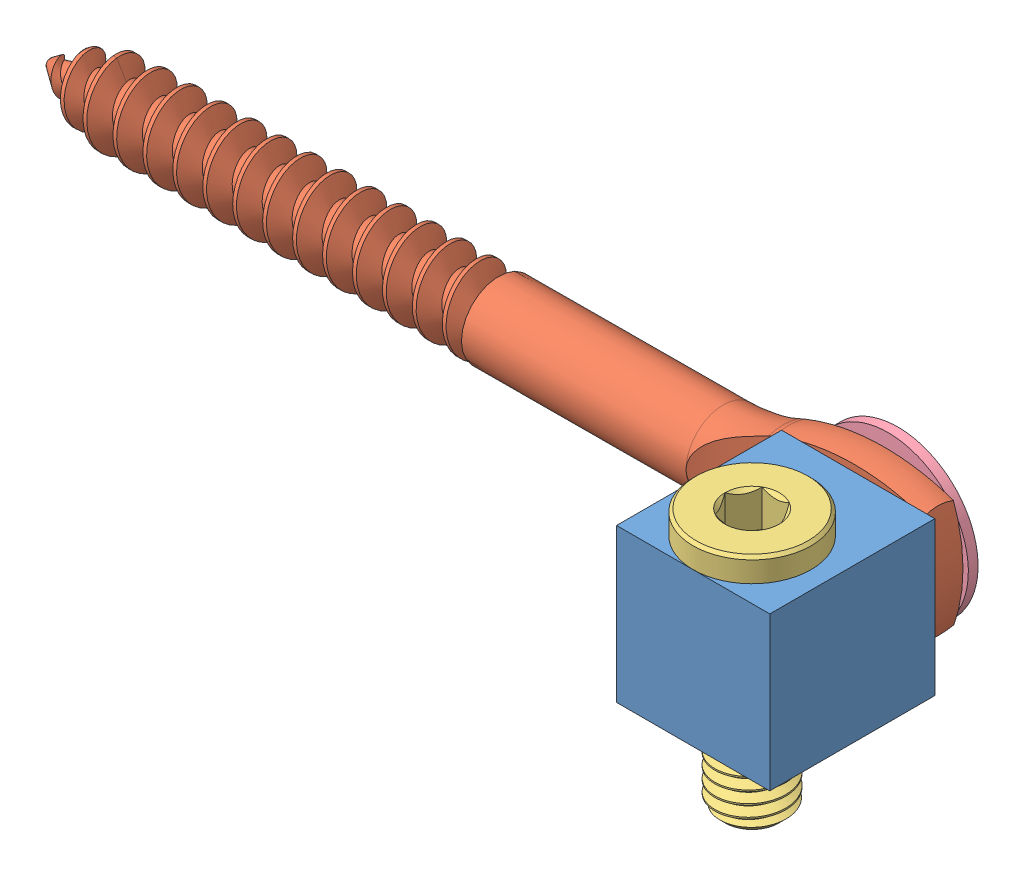
SolidWorks assembly Sample Rock Positioning Assembly 2, configuration Default. Lengths in mm.
Overall size (79.23 24.28 20.07).
4 component instances, 4 part files, 16 mates.
Components (placement in the parent):
- Sample Rock Positioning Bracket 2-1: Sample Rock Positioning Bracket 2 [Default] at (4.3735 9.6175 7.5401) size (13 13 14)
- 90171A554_SCREW HANGER-1: 90171A554_SCREW HANGER [90171A554] at (-65.4758 10.8048 6.2701) x (0 0 1) z (-0.99999 -0.004477 0) size (7.33 13.07 76.67)
- 90358A019_METRIC STL ULTRA-LOW-PROFILE SCKT HEAD SCREW-1: 90358A019_METRIC STL ULTRA-LOW-PROFILE SCKT HEAD SCREW [90358A019] at (4.3735 6.1175 16.5401) x (0 -1 0) z (0 0 1) size (22.63 10 10)
- 92137A523_CLASS 10.9 ALLOY STEEL BUTTON-HEAD CAP SCREW-1: 92137A523_CLASS 10.9 ALLOY STEEL BUTTON-HEAD CAP SCREW [92137A523] at (4.3735 11.1175 1.7001) x (-0.923728 -0.383049 0) z (0 0 -1) size (13.6 13.6 11.86)
Mates (geometry in assembly coordinates):
- Coincident3: coincident anti-aligned: plane of Sample Rock Positioning Bracket 2-1 through (4.3735 5.1175 16.5401) normal (0 1 0); plane of 91223A421_316 SS ULTRA-LOW-PROFILE SOCKET HEAD SCREW-1 through (4.3735 5.1175 22.5401) normal (0 -1 0)
- Concentric3: concentric anti-aligned: circle of Sample Rock Positioning Bracket 2-1; circle of 91223A421_316 SS ULTRA-LOW-PROFILE SOCKET HEAD SCREW-1
- Coincident4: coincident anti-aligned: plane of Sample Rock Positioning Bracket 2-1 through (4.3735 9.6175 7.5401) normal (0 0 -1); plane of 91290A173_BLACK-OXIDE CLASS 12.9 SOCKET HEAD CAP SCREW-1 through (4.3735 12.1175 7.5401) normal (0 0 1)
- Concentric4: concentric anti-aligned: circle of Sample Rock Positioning Bracket 2-1; circle of 91290A173_BLACK-OXIDE CLASS 12.9 SOCKET HEAD CAP SCREW-1
- Coincident6: coincident anti-aligned: plane of Sample Rock Positioning Bracket 2-1 through (-2.1265 16.1175 21.5401) normal (0 1 0); plane of 91223A442_316 SS ULTRA-LOW-PROFILE SOCKET HEAD SCREW-1 through (4.3735 16.1175 22.5401) normal (0 -1 0)
- Concentric5: concentric aligned: circle of Sample Rock Positioning Bracket 2-1; circle of 91223A442_316 SS ULTRA-LOW-PROFILE SOCKET HEAD SCREW-1
- Coincident7: coincident anti-aligned: plane of Sample Rock Positioning Bracket 2-1 through (4.3735 9.6175 7.5401) normal (0 0 -1); plane of 90171A554_SCREW HANGER-1 through (10.7803 -1.554 7.5401) normal (0 0 1)
- Concentric6: concentric aligned: circle of 90171A554_SCREW HANGER-1; cylinder of Sample Rock Positioning Bracket 2-1 through (4.3735 11.1175 7.5401) axis (0 0 -1) radius 2.5
- Coincident8: coincident anti-aligned: plane of 91290A312_BLACK-OXIDE CLASS 12.9 SOCKET HEAD CAP SCREW-1 through (4.3735 11.1175 5.0001) normal (0 0 1); plane of 90171A554_SCREW HANGER-1 through (10.7803 -1.554 5.0001) normal (0 0 -1)
- Concentric7: concentric aligned: circle of Sample Rock Positioning Bracket 2-1; circle of 91290A312_BLACK-OXIDE CLASS 12.9 SOCKET HEAD CAP SCREW-1
- Coincident9: coincident anti-aligned: plane of 90171A554_SCREW HANGER-1 through (10.7803 -1.554 5.0001) normal (0 0 -1); plane of 90358A016_METRIC STL ULTRA-LOW-PROFILE SCKT HEAD SCREW-1 through (4.3735 16.1175 5.0001) normal (0 0 1)
- Concentric8: concentric anti-aligned: circle of 90171A554_SCREW HANGER-1; circle of 90358A016_METRIC STL ULTRA-LOW-PROFILE SCKT HEAD SCREW-1
- Concentric9: concentric anti-aligned: circle of 90358A019_METRIC STL ULTRA-LOW-PROFILE SCKT HEAD SCREW-1; circle of Sample Rock Positioning Bracket 2-1
- Coincident12: coincident anti-aligned: plane of 90358A019_METRIC STL ULTRA-LOW-PROFILE SCKT HEAD SCREW-1 through (9.3735 16.1175 16.5401) normal (0 -1 0); plane of Sample Rock Positioning Bracket 2-1 through (-2.1265 16.1175 21.5401) normal (0 1 0)
- Concentric10: concentric anti-aligned: circle of 92137A523_CLASS 10.9 ALLOY STEEL BUTTON-HEAD CAP SCREW-1; circle of 90171A554_SCREW HANGER-1
- Coincident13: coincident anti-aligned: plane of 90171A554_SCREW HANGER-1 through (10.7803 -1.554 5.0001) normal (0 0 -1); plane of 92137A523_CLASS 10.9 ALLOY STEEL BUTTON-HEAD CAP SCREW-1 through (6.3271 6.4065 5.0001) normal (0 0 1)
